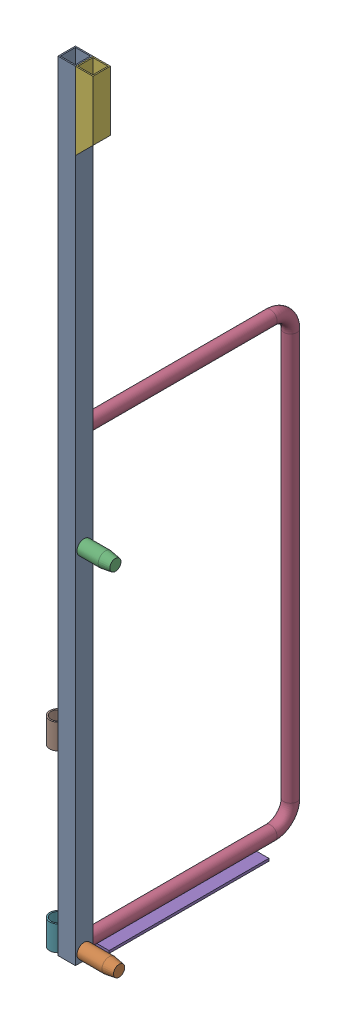
SolidWorks assembly FE-00002-R_ASM, configuration Default. Lengths in mm.
Overall size (175.51 1981.23 585.85).
8 component instances, 7 part files, 0 mates.
Components (placement in the parent):
- FE-00002-05-1: FE-00002-05 [Default] at origin size (44.45 1981.2 44.45)
- FE-00002-01-1: FE-00002-01 [Default] at (3.175 22.225 -22.225) size (130.18 36.51 36.51)
- FE-00002-02-1: FE-00002-02 [Default] at (3.175 911.225 -22.225) size (120.65 36.51 36.51)
- FE-00002-06-1: FE-00002-06 [Default] at (22.225 23.0188 -44.45) x (-1 0 0) z (0 0 1) size (33.4 1168.46 541.4)
- FE-00002-07-1: FE-00002-07 [Default] at (-15.875 -0.0318 -476.25) x (0 0 1) z (-1 0 0) size (406.4 6.35 76.2)
- FE-00002-03-1: FE-00002-03 [Default] at (44.45 1981.2 0) x (0 0 -1) z (-1 0 0) size (44.45 196.85 44.45)
- FE-00002-09-1: FE-00002-09 [Default] at (-21.082 31.75 -21.1582) size (42.16 63.5 42.16)
- FE-00002-09-2: FE-00002-09 [Default] at (-21.082 476.25 -21.1582) size (42.16 63.5 42.16)
